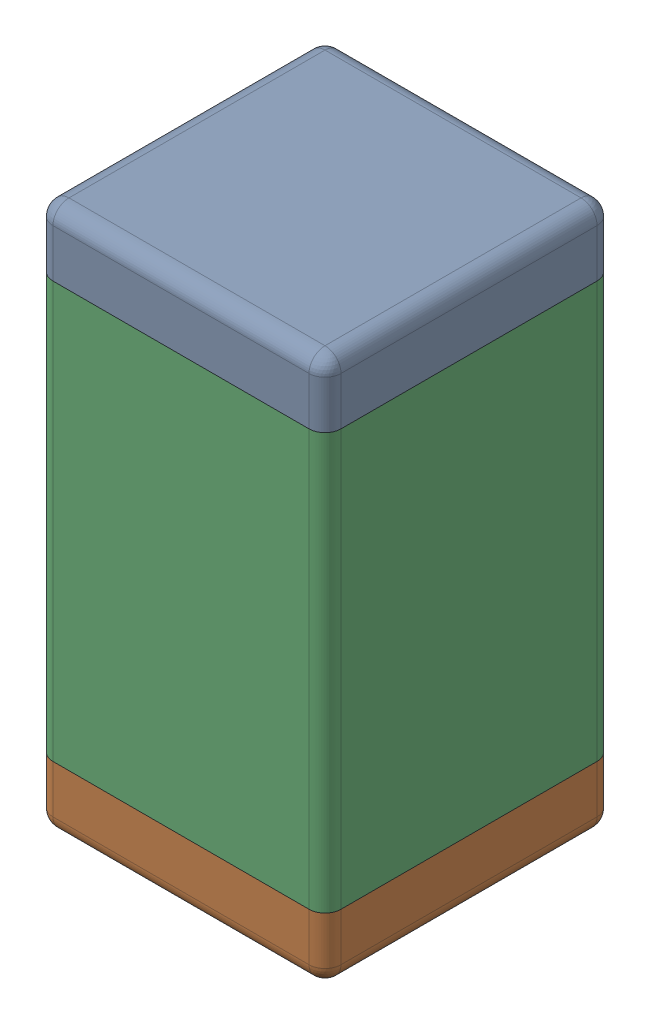
SolidWorks assembly C5, configuration Default. Lengths in mm.
Overall size (0.9 1.7 0.9).
6 component instances, 3 part files, 0 mates.
Components (placement in the parent):
- 5943011504-1: 5943011504 [Default] at (20.947 4.445 0) x (0 -1 0) z (0 0 1) size (1.7 0.9 0.9)
  - Terminal_3-1: Terminal_3 [Default] at (-0.85 -0.45 0) size (1.7 0.9 0.9)
    - Open CASCADE STEP translator 6.8 6.1.1-1: Open CASCADE STEP translator 6.8 6.1.1 [Default] at origin size (0.2 0.9 0.9)
    - Open CASCADE STEP translator 6.8 6.1.2-1: Open CASCADE STEP translator 6.8 6.1.2 [Default] at origin size (0.2 0.9 0.9)
  - Mid_Body-1: Mid_Body [Default] at (-0.85 -0.45 0) size (1.3 0.9 0.9)
    - Open CASCADE STEP translator 6.8 6.2.1-1: Open CASCADE STEP translator 6.8 6.2.1 [Default] at origin size (1.3 0.9 0.9)
